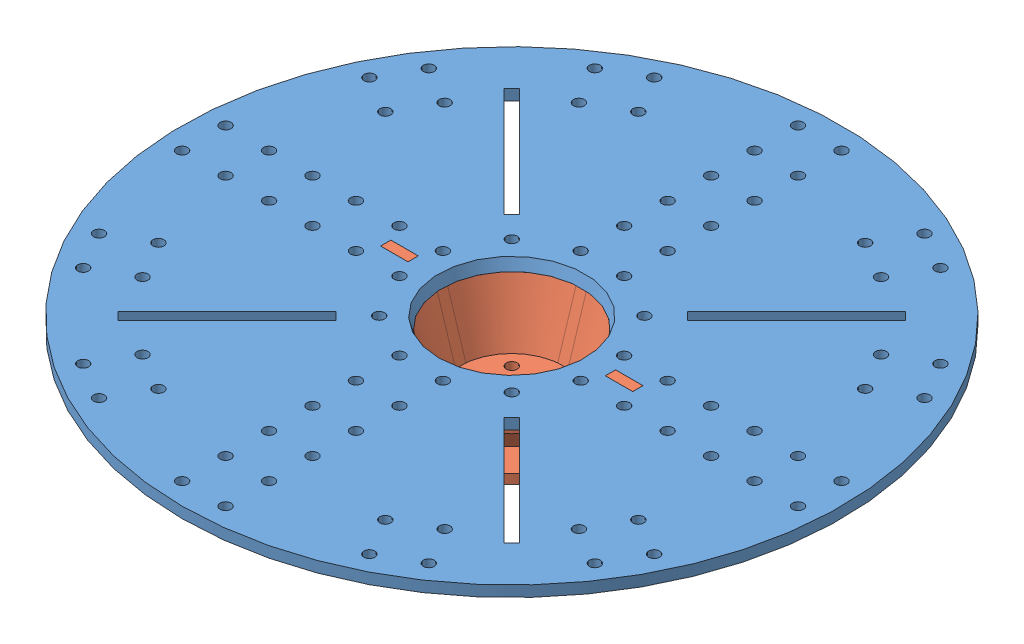
SolidWorks assembly BaseStructure, configuration Default. Lengths in mm.
Overall size (385.3 46.25 385.3).
2 component instances, 2 part files, 3 mates.
Components (placement in the parent):
- BodyPlate_bigger-1: BodyPlate_bigger [Default] at (-22.9439 32.8916 5.4719) size (385.3 46.25 385.3)
- PlateSupport_big-1: PlateSupport_big [Default] at (-22.9439 32.8916 5.4719) size (240 46.25 240)
Mates (geometry in assembly coordinates):
- Coincident1: coincident anti-aligned: plane of BodyPlate_bigger-1 through (34.7059 26.5416 2.4719) normal (1 0 0); plane of PlateSupport_big-1 through (34.7059 26.5416 2.4719) normal (-1 0 0)
- Coincident2: coincident anti-aligned: plane of BodyPlate_bigger-1 through (50.7059 26.5416 2.4719) normal (-1 0 0); plane of PlateSupport_big-1 through (50.7059 26.5416 2.4719) normal (1 0 0)
- Coincident3: coincident aligned: line of BodyPlate_bigger-1 through (34.7059 32.8916 2.4719) axis (1 0 0); line of PlateSupport_big-1 through (34.7059 32.8916 2.4719) axis (1 0 0)
